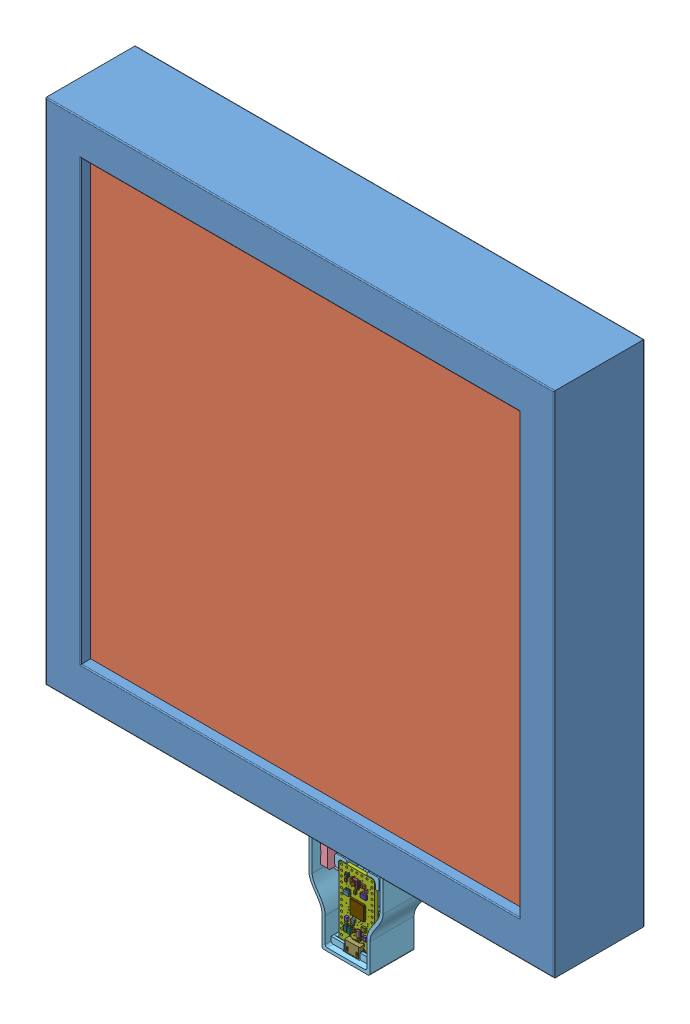
SolidWorks assembly _full_assy, configuration Default. Lengths in mm.
Overall size (254 326.02 47).
45 component instances, 29 part files, 9 mates.
Components (placement in the parent):
- RIBBA-1: RIBBA [Default] at (0 127 45) size (254 254 45)
  - Outer^RIBBA-1: Outer^RIBBA [Default] at origin size (254 254 45) (virtual)
  - Glass^RIBBA-1: Glass^RIBBA [Default] at (0 0 -5) x (-1 0 0) z (0 0 -1) size (232 232 2) (virtual)
  - Inner^RIBBA-1: Inner^RIBBA [Default] at (0 0 -7) x (-1 0 0) z (0 0 -1) size (230 230 30) (virtual)
  - Matte^RIBBA-1: Matte^RIBBA [Default] at (0 0 -37) x (-1 0 0) z (0 0 -1) size (230 230 1.1) (hidden, virtual)
  - Back^RIBBA-1: Back^RIBBA [Default] at (0 0 -38.1) x (-1 0 0) z (0 0 -1) size (230 230 2.65) (virtual)
- mcu_enclosure-2: mcu_enclosure [Default] at (0 -68 2) x (1 0 0) z (0 -1 0) size (38.82 24.11 78.62)
  - mcu_enclosure-1: mcu_enclosure [Default] at origin size (37 22 68)
  - Lumberg_1614_10-1: Lumberg_1614_10 [Default] at (0 6 0) x (0 -1 0) z (0 0 1) size (10 10 17.01)
    - Lumberg_1614_10.stp-1: Lumberg_1614_10.stp [Default] at (0.8468 0.2582 0) size (13.42 14.23 17.01)
      - ID_1.stp-1: ID_1.stp [Default] at (-0.8468 -0.2582 0) size (10 10 17.01)
      - ID_1-0.stp-1: ID_1-0.stp [Default] at (-0.8365 -0.3028 -2.0087) x (-0.358368 0.93358 0) z (0 0 1) size (11.4 10 2.51) (hidden)
  - 3800 ItsyBitsy M4-1: 3800 ItsyBitsy M4 [Default] at (8.89 13 -1.6) x (0 0 -1) z (0 1 0) size (36.02 17.78 4.34)
    - 3800-ItsyBitsy-M4.step-1: 3800-ItsyBitsy-M4.step [Default] at origin size (36.02 17.78 4.34)
      - PCB Component.step-1: PCB Component.step [Default] at origin size (36.02 17.78 4.34)
        - Board.step-1: Board.step [Default] at origin size (35.56 17.78 1.57)
        - 10_X_B5F.step-1: 10_X_B5F.step [Default] at (12.578 13.375 1.57) size (2 1.25 1)
        - 10_X_B5F.step-2: 10_X_B5F.step [Default] at (8.449 4.176 1.57) x (-1 0 0) z (0 0 1) size (2 1.25 1)
        - 100k.step-1: 100k.step [Default] at (11.447 10.782 1.57) x (0 1 0) z (0 0 1) size (1.6 0.9 0.8)
        - 100k.step-2: 100k.step [Default] at (6.768 7.163 1.57) x (0 1 0) z (0 0 1) size (1.6 0.9 0.8)
        - 100k.step-3: 100k.step [Default] at (29.21 13.78 1.57) size (1.6 0.9 0.8)
        - 100k.step-4: 100k.step [Default] at (28.321 8.318 1.57) x (0 1 0) z (0 0 1) size (1.6 0.9 0.8)
        - 100k.step-5: 100k.step [Default] at (9.144 10.033 1.57) x (-1 0 0) z (0 0 1) size (1.6 0.9 0.8)
        - 100k.step-6: 100k.step [Default] at (26.035 9.208 1.57) x (-1 0 0) z (0 0 1) size (1.6 0.9 0.8)
        - RED.step-1: RED.step [Default] at (31.536 13.376 1.57) x (-1 0 0) z (0 0 1) size (1.25 2.02 1.1)
        - SPST_TACT-KMR2.step-1: SPST_TACT-KMR2.step [Default] at (30.48 9.017 1.57) x (0 -1 0) z (0 0 1) size (4.6 2.8 1.94)
        - microUSB.step-1: microUSB.step [Default] at (4.445 8.89 1.57) x (0 -1 0) z (0 0 1) size (8.8 5.6 3)
        - AP2112K-3.3.step-1: AP2112K-3.3.step [Default] at (9.271 7.239 1.57) x (-1 0 0) z (0 0 1) size (3 3 1.4)
        - 74HCT1G125DBV.step-1: 74HCT1G125DBV.step [Default] at (24.066 13.081 1.57) x (0 1 0) z (0 0 1) size (3 3 1.4)
        - MBR120.step-1: MBR120.step [Default] at (8.572 13.462 1.57) x (-1 0 0) z (0 0 1) size (3.6 1.4 1.35)
        - MBR120.step-2: MBR120.step [Default] at (8.572 11.684 1.57) x (-1 0 0) z (0 0 1) size (3.6 1.4 1.35)
        - AP102-2020.step-1: AP102-2020.step [Default] at (12.065 4.826 1.57) size (2 2 0.9)
        - GD25x16.step-1: GD25x16.step [Default] at (26.289 5.144 1.57) x (0 -1 0) z (0 0 1) size (3 2 0.8)
        - ATSAMD51G_TQFN48.step-1: ATSAMD51G_TQFN48.step [Default] at (19.177 7.938 1.57) size (7 7 1)
        - 10uF.step-1: 10uF.step [Default] at (13.272 10.224 1.57) x (0 1 0) z (0 0 1) size (2 1.25 0.85)
        - 1uF.step-1: 1uF.step [Default] at (29.02 3.874 1.57) size (1.6 0.9 0.8)
        - 1uF.step-2: 1uF.step [Default] at (30.48 4.89 1.57) x (-1 0 0) z (0 0 1) size (1.6 0.9 0.8)
        - 1uF.step-3: 1uF.step [Default] at (30.48 5.906 1.57) size (1.6 0.9 0.8)
  - GP2Y0A02YK0F SHARP_edited-1: GP2Y0A02YK0F SHARP_edited [Default] at (0 0 -55.65) x (1 0 0) z (0 1 0) size (30.02 18.9 21.6)
  - 1119 12mm-TactileSwitch-1: 1119 12mm-TactileSwitch [Default] at (-13.15 10 -37) x (0 0 -1) z (0 1 0) size (12.91 8.96 12)
  - ELCO_8x15mm-1: ELCO_8x15mm [Default] at (0 5.9842 -17.4502) x (-1 0 0) z (0 -1 0) size (8 20 8)
  - LED_cables-1: LED_cables [Default] at (0 -1 -74.6) x (1 0 0) z (0 1 0) size (17.6 30 16.6)
  - mcu_enclosure_lid-1: mcu_enclosure_lid [Default] at (0 20 0) x (-1 0 0) z (0 0 1) size (38.82 20.11 68) (hidden)
  - DIN EN ISO 7046-1 - M3 x 8 - Z - 8N-1: DIN EN ISO 7046-1 - M3 x 8 - Z - 8N [DIN EN ISO 7046-1 - M3 x 8 - Z - 8N] at (0 -1.65 -39.988) x (0 1 0) z (-0.613802 0 -0.78946) size (8 5.5 5.5)
- suspension_plate-1: suspension_plate [Default] at (0 -12 0) size (30 27.2 5)
Mates (geometry in assembly coordinates):
- Coincident14: coincident anti-aligned: plane of RIBBA-1/Outer^RIBBA-1 through (0 127 0) normal (0 0 -1)
- Coincident7: coincident aligned: plane of RIBBA-1 through (0 127 45) normal (1 0 0)
- Coincident15: coincident anti-aligned: plane of RIBBA-1/Outer^RIBBA-1 through (127 0 0) normal (0 -1 0)
- Coincident16: coincident anti-aligned: plane of mcu_enclosure-2/mcu_enclosure-1 through (-15.25 -45.5 0) normal (0 0 -1)
- Coincident17: coincident aligned: plane of mcu_enclosure-2 through (0 -68 2) normal (1 0 0)
- Coincident18: coincident anti-aligned: plane of RIBBA-1/Outer^RIBBA-1 through (127 0 0) normal (0 -1 0); plane of mcu_enclosure-2/mcu_enclosure-1 through (-18.5 0 0) normal (0 1 0)
- Coincident19: coincident aligned: plane of mcu_enclosure-2/mcu_enclosure-1 through (0 -10 2) normal (0 1 0); plane of suspension_plate-1 through (0 -10 0) normal (0 1 0)
- Coincident20: coincident aligned: plane of suspension_plate-1 through (0 -12 0) normal (1 0 0)
- Coincident21: coincident anti-aligned: plane of mcu_enclosure-2/mcu_enclosure-1 through (-15.25 -45.5 0) normal (0 0 -1); plane of suspension_plate-1 through (0 -12 0) normal (0 0 1)
